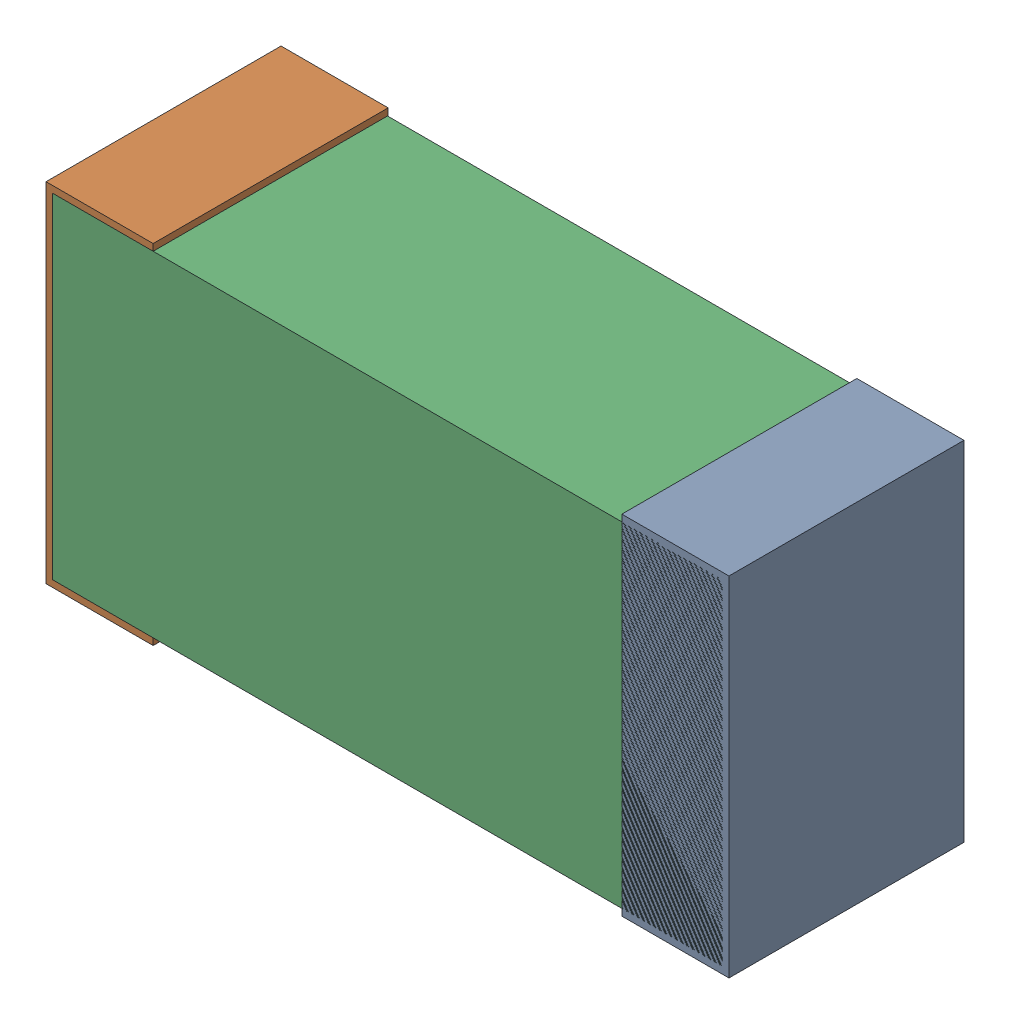
SolidWorks assembly C16, configuration Default. Lengths in mm.
Overall size (1.02 0.52 0.35).
6 component instances, 2 part files, 0 mates.
Components (placement in the parent):
- 870940480-1: 870940480 [Default] at (54.582 34.6434 -1.9516) size (0.16 0.52 0.35)
  - Extruded-1: Extruded [Default] at origin size (0.16 0.52 0.35)
- 870940480-2: 870940480 [Default] at (53.722 34.6434 -1.9516) size (0.16 0.52 0.35)
  - Extruded-1: Extruded [Default] at origin size (0.16 0.52 0.35)
- 870940640-1: 870940640 [Default] at (54.152 34.6434 -1.9506) size (1 0.5 0.35)
  - Extruded_2-1: Extruded_2 [Default] at origin size (1 0.5 0.35)
